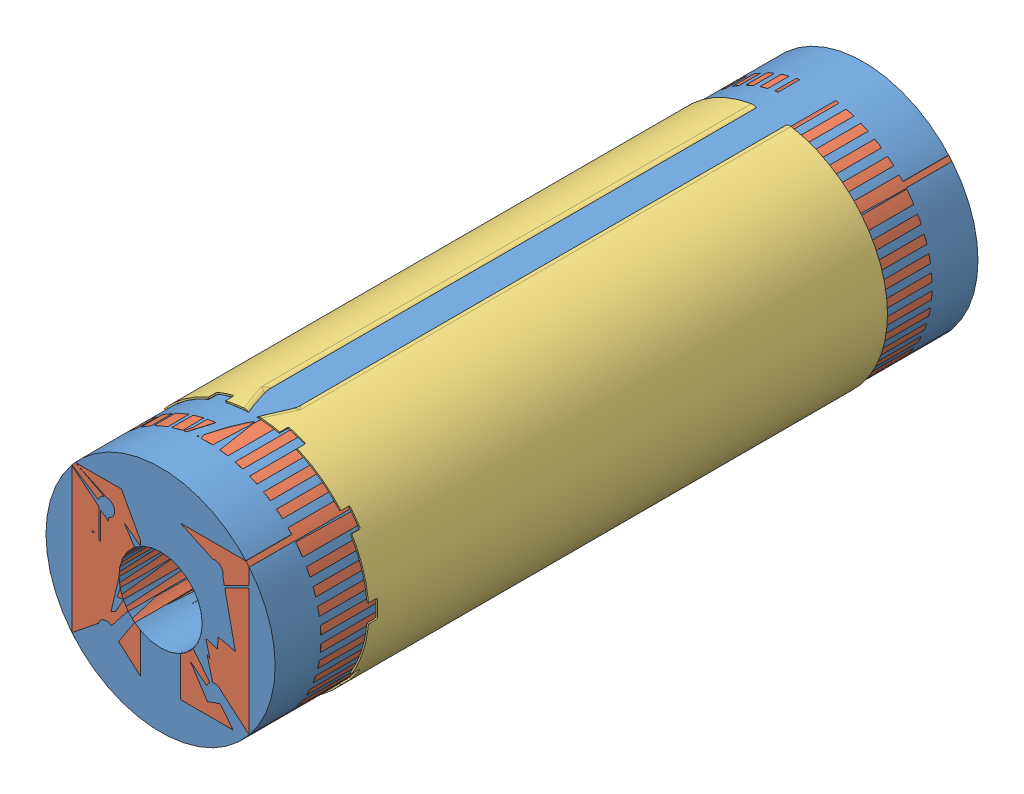
SolidWorks assembly tt_mandrel_blank, configuration Default. Lengths in mm.
Overall size (152 152.12 460).
5 component instances, 3 part files, 12 mates.
Components (placement in the parent):
- tt_mandrel_blank-1: tt_mandrel_blank [Default] at origin size (150 150 460) (hidden)
- tt_mandrel-1: tt_mandrel [with trim guides] at (0 0 170) size (73.14 149.99 460)
- tt_mandrel-2: tt_mandrel [extended] at (0 0 170) x (-1 0 0) z (0 0 1) size (84.13 150 460)
- transition_tube_cyl _v4_u-1: transition_tube_cyl _v4_u [Default] at (0 0 170) size (75.27 152.12 339.5)
- transition_tube_cyl _v4_u-2: transition_tube_cyl _v4_u [Default] at (0 0 170) x (-1 0 0) z (0 0 1) size (75.27 152.12 339.5)
Mates (geometry in assembly coordinates):
- Coincident1: coincident aligned: plane of tt_mandrel-1 through (0 0 170) normal (0 1 0); plane of assembly through (0 0 0) normal (0 1 0)
- Coincident2: coincident anti-aligned: plane of tt_mandrel-2; plane of assembly through (0 0 0) normal (0 1 0)
- Coincident3: coincident aligned: plane of tt_mandrel-1 through (0 0 170) normal (1 0 0); plane of assembly through (0 0 0) normal (1 0 0)
- Coincident4: coincident anti-aligned: plane of tt_mandrel-2; plane of assembly through (0 0 0) normal (1 0 0)
- Coincident5: coincident aligned: plane of tt_mandrel-2 through (0 0 842.8962) normal (0 1 0); plane of assembly through (0 0 0) normal (0 1 0)
- Coincident6: coincident aligned: plane of tt_mandrel_blank-1 through (0 0 230) normal (0 0 1); plane of tt_mandrel-1 through (0 0 230) normal (0 0 1)
- Coincident7: coincident aligned: plane of tt_mandrel-1 through (0 0 230) normal (0 0 1); plane of tt_mandrel-2 through (0 0 230) normal (0 0 1)
- Coincident8: coincident aligned: line of tt_mandrel-1 through (0 0 89.1) axis (0 0 1); line of transition_tube_cyl _v4_u-1 through (0 0 89.1) axis (0 0 1)
- Coincident9: coincident anti-aligned: plane of tt_mandrel-1 through (-9 -76 150.5386) normal (1 0 0); plane of transition_tube_cyl _v4_u-1 through (-9 -76 150.5386) normal (-1 0 0)
- Coincident10: coincident aligned: plane of tt_mandrel-1 through (-12.2 33.0182 -169.75) normal (0 0 -1); plane of transition_tube_cyl _v4_u-1 through (0 -76.0648 -169.75) normal (0 0 -1)
- Coincident11: coincident aligned: line of tt_mandrel-2 through (0 0 89.1) axis (0 0 1); line of transition_tube_cyl _v4_u-2 through (0 0 89.1) axis (0 0 1)
- Coincident12: coincident anti-aligned: plane of tt_mandrel-2 through (1.8629 76 170.3417) normal (-0.939793 0 -0.341743); plane of transition_tube_cyl _v4_u-2 through (1.8629 76 170.3417) normal (0.939793 0 0.341743)
